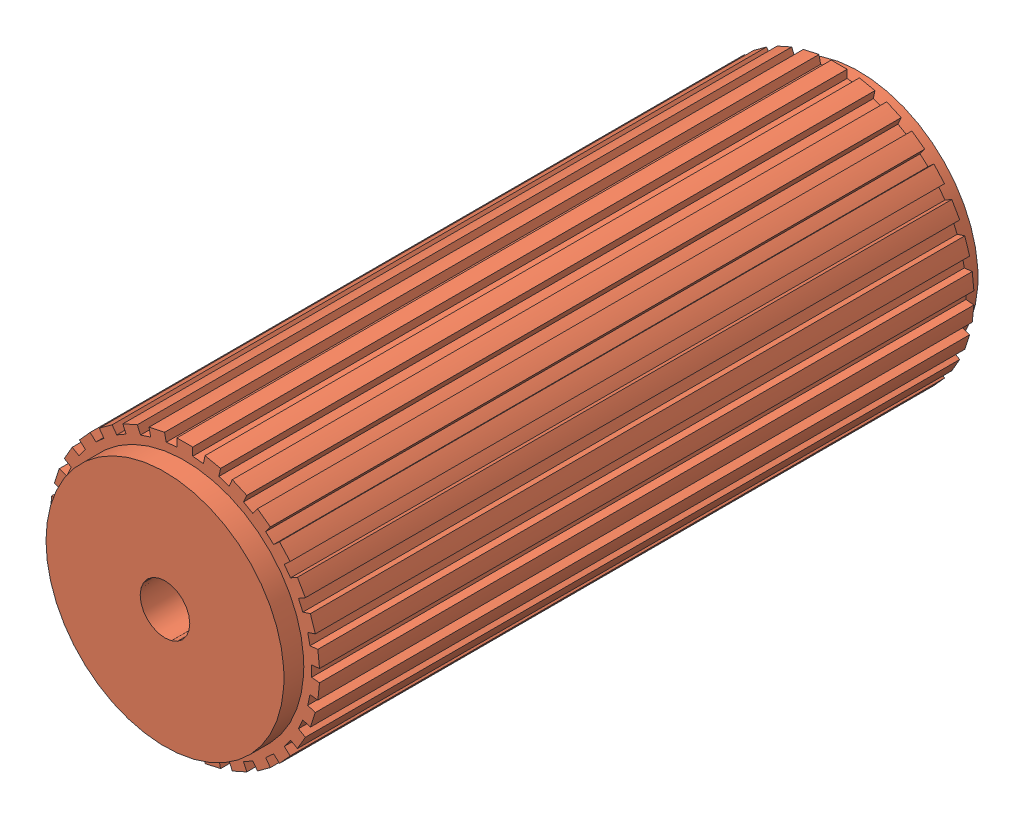
SolidWorks assembly Assem2, configuration Default. Lengths in mm.
Overall size (193.28 149.38 350).
2 component instances, 2 part files, 1 mates.
Components (placement in the parent):
- ring-1: ring [Default] at origin size (115 15 115)
- roller-1: roller [Default] at (67.8564 73.8831 -175) size (135.86 136 350)
Mates (geometry in assembly coordinates):
- Coincident1: coincident anti-aligned: plane of ring-1 through (0 0 0) normal (0 0 1); plane of roller-1 through (67.8564 73.8831 0) normal (0 0 -1)
